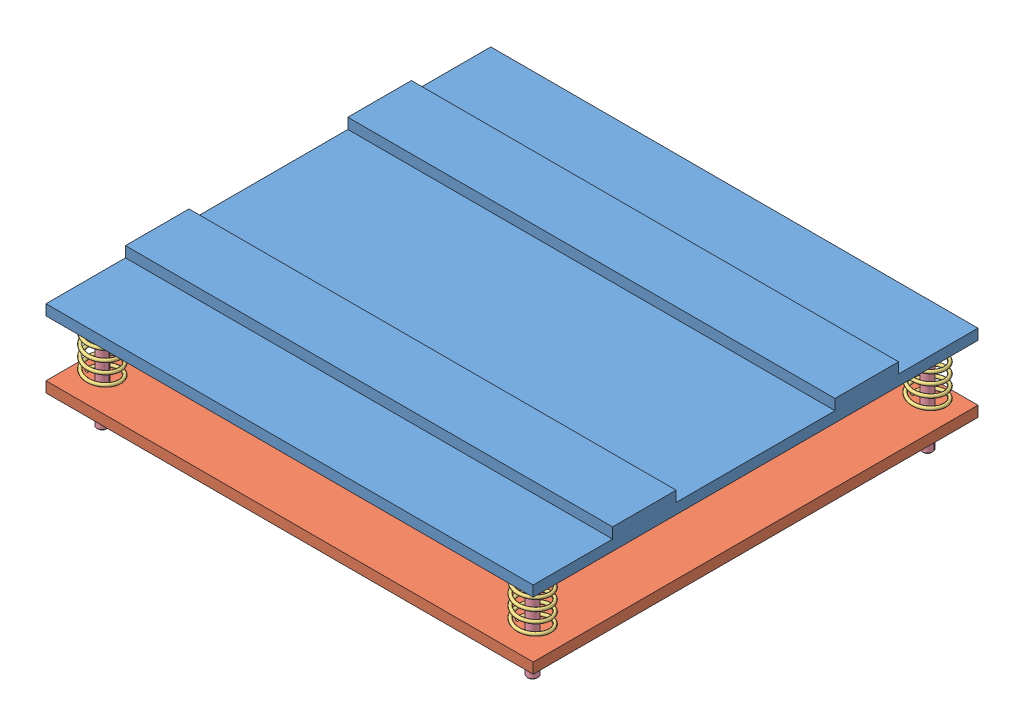
SolidWorks assembly Assem1, configuration Default. Lengths in mm.
Overall size (230 55 210).
14 component instances, 5 part files, 24 mates.
Components (placement in the parent):
- Part4-1: Part4 [Default] at (-116.887 -20.5528 -75.9837) size (230 10 210)
- Part3-1: Part3 [Default] at (29.2094 -47.0514 4.8523) x (0 0 -1) z (-1 0 0) size (210 5 230)
- Part5-1: Part5 [Default] at (-118.7637 -46.3117 -72.2056) size (16.52 28.04 16.52)
- Part5-2: Part5 [Default] at (-118.3534 -46.3117 111.3835) size (16.52 28.04 16.52)
- Part5-3: Part5 [Default] at (86.0231 -46.3117 -73.8497) size (16.52 28.04 16.52)
- Part5-4: Part5 [Default] at (85.0495 -46.3117 111.6262) size (16.52 28.04 16.52)
- socket countersunk head screw_am-5: socket countersunk head screw_am [B18.3.5M - 5 x 0.8 x 50 Socket FCHS  -- 50N] at (-118.3534 -15.5528 111.3835) x (0 -1 0) z (0 0 1) size (50 9.75 9.75)
- socket countersunk head screw_am-6: socket countersunk head screw_am [B18.3.5M - 5 x 0.8 x 50 Socket FCHS  -- 50N] at (85.0495 -15.5528 111.6262) x (0 -1 0) z (0 0 1) size (50 9.75 9.75)
- socket countersunk head screw_am-7: socket countersunk head screw_am [B18.3.5M - 5 x 0.8 x 50 Socket FCHS  -- 50N] at (86.0231 -15.5528 -73.8497) x (0 -1 0) z (0 0 1) size (50 9.75 9.75)
- socket countersunk head screw_am-8: socket countersunk head screw_am [B18.3.5M - 5 x 0.8 x 50 Socket FCHS  -- 50N] at (-118.7637 -15.5528 -72.2056) x (0 -1 0) z (0.680287 0 0.732946) size (50 9.75 9.75)
- hex nut style 1_am-1: hex nut style 1_am [B18.2.4.1M - Hex nut, Style 1,  M5 x 0.8 --D-N] at (86.0231 -56.7514 -73.8497) x (1 0 0) z (0 -1 0) size (8 9.24 4.7)
- hex nut style 1_am-2: hex nut style 1_am [B18.2.4.1M - Hex nut, Style 1,  M5 x 0.8 --D-N] at (-118.7637 -56.7514 -72.2056) x (1 0 0) z (0 -1 0) size (8 9.24 4.7)
- hex nut style 1_am-3: hex nut style 1_am [B18.2.4.1M - Hex nut, Style 1,  M5 x 0.8 --D-N] at (-118.3534 -56.7514 111.3835) x (1 0 0) z (0 -1 0) size (8 9.24 4.7)
- hex nut style 1_am-4: hex nut style 1_am [B18.2.4.1M - Hex nut, Style 1,  M5 x 0.8 --D-N] at (85.0495 -56.7514 111.6262) x (1 0 0) z (0 -1 0) size (8 9.24 4.7)
Mates (geometry in assembly coordinates):
- Coincident1: coincident: plane of Part4-1 through (-116.887 -20.5528 -75.9837) normal (0 -1 0); line of Part5-3 through (78.4703 -20.5528 -73.8497) axis (1 0 0)
- Coincident2: coincident: plane of Part4-1 through (-116.887 -20.5528 -75.9837) normal (0 -1 0); line of Part5-1 through (-126.3165 -20.5528 -72.2056) axis (1 0 0)
- Coincident3: coincident: plane of Part4-1 through (-116.887 -20.5528 -75.9837) normal (0 -1 0); line of Part5-2 through (-125.9063 -20.5528 111.3835) axis (1 0 0)
- Coincident4: coincident: plane of Part4-1 through (-116.887 -20.5528 -75.9837) normal (0 -1 0); line of Part5-4 through (77.4966 -20.5528 111.6262) axis (1 0 0)
- Coincident5: coincident: plane of Part3-1 through (29.2094 -47.0514 4.8523) normal (0 1 0); line of Part5-4 through (77.3714 -47.0514 111.6262) axis (1 0 0)
- Parallel1: parallel anti-aligned: plane of Part4-1 through (-131.8559 -15.5528 -85.5391) normal (0 0 -1); plane of Part3-1 through (98.1441 -52.0514 124.4609) normal (0 0 1)
- Coincident7: coincident aligned: plane of Part4-1 through (-131.8559 -15.5528 -85.5391) normal (-1 0 0); plane of Part3-1 through (-131.8559 -52.0514 124.4609) normal (-1 0 0)
- Coincident8: coincident aligned: plane of Part4-1 through (-131.8559 -15.5528 124.4609) normal (0 0 1); plane of Part3-1 through (98.1441 -52.0514 124.4609) normal (0 0 1)
- Concentric5: concentric aligned: circle of Part5-2; cylinder of socket countersunk head screw_am-5 through (-118.3534 -15.5528 111.3835) axis (0 1 0) radius 2.5
- Coincident13: coincident aligned: plane of Part4-1 through (-116.887 -15.5528 -75.9837) normal (0 1 0); plane of socket countersunk head screw_am-5 through (-118.3534 -15.5528 111.3835) normal (0 1 0)
- Concentric6: concentric aligned: circle of Part5-1; cylinder of socket countersunk head screw_am-8 through (-118.7637 -15.5528 -72.2056) axis (0 1 0) radius 2.5
- Concentric7: concentric aligned: circle of Part5-3; cylinder of socket countersunk head screw_am-7 through (86.0231 -15.5528 -73.8497) axis (0 1 0) radius 2.5
- Concentric8: concentric aligned: circle of Part5-4; cylinder of socket countersunk head screw_am-6 through (85.0495 -15.5528 111.6262) axis (0 1 0) radius 2.5
- Coincident14: coincident aligned: plane of Part4-1 through (-116.887 -15.5528 -75.9837) normal (0 1 0); plane of socket countersunk head screw_am-8 through (-118.7637 -15.5528 -72.2056) normal (0 1 0)
- Coincident15: coincident aligned: plane of Part4-1 through (-116.887 -15.5528 -75.9837) normal (0 1 0); plane of socket countersunk head screw_am-6 through (85.0495 -15.5528 111.6262) normal (0 1 0)
- Coincident16: coincident aligned: plane of Part4-1 through (-116.887 -15.5528 -75.9837) normal (0 1 0); plane of socket countersunk head screw_am-7 through (86.0231 -15.5528 -73.8497) normal (0 1 0)
- Concentric9: concentric anti-aligned: cylinder of socket countersunk head screw_am-7 through (86.0231 -15.5528 -73.8497) axis (0 1 0) radius 2.5; cylinder of hex nut style 1_am-1 through (86.0231 -52.0514 -73.8497) axis (0 -1 0) radius 2.1
- Concentric10: concentric anti-aligned: cylinder of socket countersunk head screw_am-6 through (85.0495 -15.5528 111.6262) axis (0 1 0) radius 2.5; cylinder of hex nut style 1_am-4 through (85.0495 -52.0514 111.6262) axis (0 -1 0) radius 2.1
- Concentric11: concentric anti-aligned: cylinder of socket countersunk head screw_am-8 through (-118.7637 -15.5528 -72.2056) axis (0 1 0) radius 2.5; cylinder of hex nut style 1_am-2 through (-118.7637 -52.0514 -72.2056) axis (0 -1 0) radius 2.1
- Concentric12: concentric anti-aligned: cylinder of socket countersunk head screw_am-5 through (-118.3534 -15.5528 111.3835) axis (0 1 0) radius 2.5; cylinder of hex nut style 1_am-3 through (-118.3534 -52.0514 111.3835) axis (0 -1 0) radius 2.1
- Coincident17: coincident anti-aligned: plane of Part3-1 through (29.2094 -52.0514 4.8523) normal (0 -1 0); plane of hex nut style 1_am-1 through (78.0231 -52.0514 -73.8497) normal (0 1 0)
- Coincident18: coincident anti-aligned: plane of Part3-1 through (29.2094 -52.0514 4.8523) normal (0 -1 0); plane of hex nut style 1_am-4 through (77.0495 -52.0514 111.6262) normal (0 1 0)
- Coincident19: coincident anti-aligned: plane of Part3-1 through (29.2094 -52.0514 4.8523) normal (0 -1 0); plane of hex nut style 1_am-3 through (-126.3534 -52.0514 111.3835) normal (0 1 0)
- Coincident20: coincident anti-aligned: plane of Part3-1 through (29.2094 -52.0514 4.8523) normal (0 -1 0); plane of hex nut style 1_am-2 through (-126.7637 -52.0514 -72.2056) normal (0 1 0)
